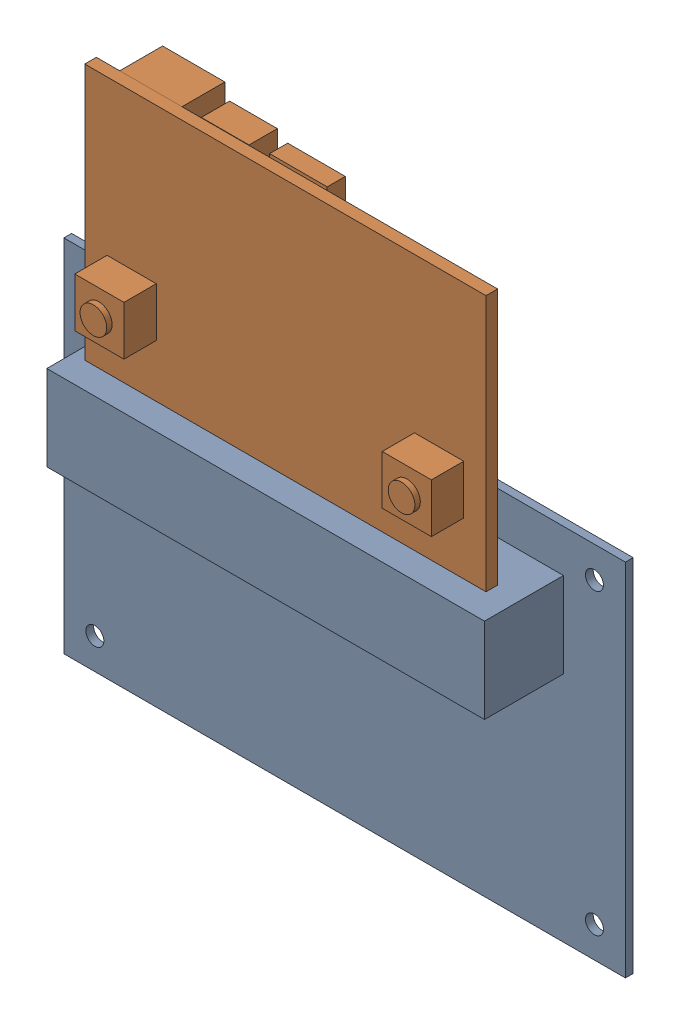
SolidWorks assembly assemblage carte alim + microbit, configuration Défaut. Lengths in mm.
Overall size (72.5 74.52 12.69).
2 component instances, 2 part files, 0 mates.
Components (placement in the parent):
- carte alim-1: carte alim [Défaut] at (-29.7632 -22.0429 1000) size (72.5 46.5 11.2)
- carte microbit-1: carte microbit [Défaut] at (27.2824 52.0666 1007.8196) x (-1 0 0) z (0 1 0) size (51.8 11.92 42.41)
